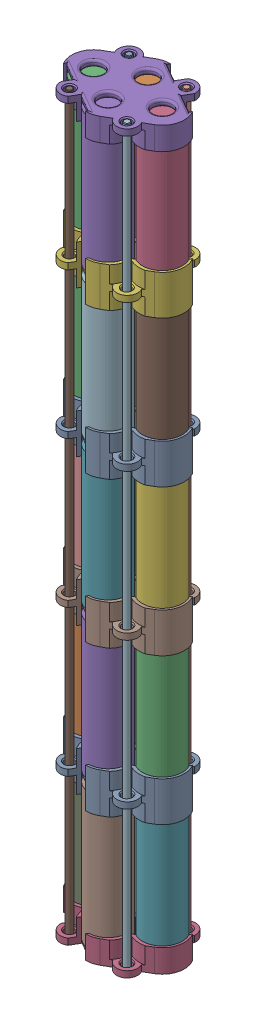
SolidWorks assembly batterySpacersAssembly_V2, configuration Default. Lengths in mm.
Overall size (58.15 352.38 42.71).
30 component instances, 6 part files, 36 mates.
Components (placement in the parent):
- batterySpacerMid-1: batterySpacerMid [Default] at (-19.5706 2.8185 8.4123) size (53.91 19 40)
- batteryCell-1: batteryCell [Default] at (-36.0251 3.8185 8.4123) x (-0.639427 0 0.768852) z (-0.768852 0 -0.639427) size (18 65 18)
- batteryCell-33: batteryCell [Default] at (-3.1161 3.8185 8.4123) x (0.922669 0 0.385592) z (-0.385592 0 0.922669) size (18 65 18)
- batteryCell-38: batteryCell [Default] at (-19.5706 3.8185 -1.0877) x (-0.259377 0 0.965776) z (-0.965776 0 -0.259377) size (18 65 18)
- batteryCell-43: batteryCell [Default] at (-19.5706 3.8185 17.9123) x (-0.999982 0 -0.006076) z (0.006076 0 -0.999982) size (18 65 18)
- batteryCell-34: batteryCell [Default] at (-3.1161 73.8185 8.4123) x (0.922669 0 0.385592) z (-0.385592 0 0.922669) size (18 65 18)
- batteryCell-44: batteryCell [Default] at (-19.5706 73.8185 17.9123) x (-0.999982 0 -0.006076) z (0.006076 0 -0.999982) size (18 65 18)
- batterySpacerMid-2: batterySpacerMid [Default] at (-19.5706 72.8185 8.4123) size (53.91 19 40)
- batteryCell-39: batteryCell [Default] at (-19.5706 73.8185 -1.0877) x (-0.259377 0 0.965776) z (-0.965776 0 -0.259377) size (18 65 18)
- batteryCell-8: batteryCell [Default] at (-36.0251 73.8185 8.4123) x (-0.639427 0 0.768852) z (-0.768852 0 -0.639427) size (18 65 18)
- batteryCell-35: batteryCell [Default] at (-3.1161 143.8185 8.4123) x (0.922669 0 0.385592) z (-0.385592 0 0.922669) size (18 65 18)
- batteryCell-45: batteryCell [Default] at (-19.5706 143.8185 17.9123) x (-0.999982 0 -0.006076) z (0.006076 0 -0.999982) size (18 65 18)
- batterySpacerMid-3: batterySpacerMid [Default] at (-19.5706 142.8185 8.4123) size (53.91 19 40)
- batteryCell-40: batteryCell [Default] at (-19.5706 143.8185 -1.0877) x (-0.259377 0 0.965776) z (-0.965776 0 -0.259377) size (18 65 18)
- batteryCell-12: batteryCell [Default] at (-36.0251 143.8185 8.4123) x (-0.639427 0 0.768852) z (-0.768852 0 -0.639427) size (18 65 18)
- batterySpacerBottom-1: batterySpacerBottom [Default] at (-19.5706 -67.1815 8.4123) size (53.91 11.13 40)
- batterySpacerTop-1: batterySpacerTop [Default] at (-19.5706 281.8185 8.4123) size (53.91 11.13 40)
- batteryCell-48: batteryCell [Default] at (-19.5706 -66.1815 -1.0877) x (0.182331 0 0.983237) z (-0.983237 0 0.182331) size (18 65 18)
- batteryCell-49: batteryCell [Default] at (-3.1161 -66.1815 8.4123) x (0.585913 0 0.810374) z (-0.810374 0 0.585913) size (18 65 18)
- batteryCell-50: batteryCell [Default] at (-19.5706 -66.1815 17.9123) x (0.644166 0 0.764886) z (-0.764886 0 0.644166) size (18 65 18)
- batteryCell-51: batteryCell [Default] at (-36.0251 -66.1815 8.4123) x (-0.258821 0 0.965925) z (-0.965925 0 -0.258821) size (18 65 18)
- threadedShaft-1: threadedShaft [Default] at (-5.8434 -70.4315 -5.864) size (3 352.25 3)
- threadedShaft-2: threadedShaft [Default] at (-33.2979 -70.4315 22.6886) size (3 352.25 3)
- threadedShaft-3: threadedShaft [Default] at (-5.8434 -70.4315 22.6886) size (3 352.25 3)
- threadedShaft-4: threadedShaft [Default] at (-33.2979 -70.4315 -5.864) size (3 352.25 3)
- batteryCell-41: batteryCell [Default] at (-19.5706 213.8185 -1.0877) x (-0.259377 0 0.965776) z (-0.965776 0 -0.259377) size (18 65 18)
- batteryCell-31: batteryCell [Default] at (-36.0251 213.8185 8.4123) x (-0.639427 0 0.768852) z (-0.768852 0 -0.639427) size (18 65 18)
- batteryCell-36: batteryCell [Default] at (-3.1161 213.8185 8.4123) x (0.922669 0 0.385592) z (-0.385592 0 0.922669) size (18 65 18)
- batteryCell-46: batteryCell [Default] at (-19.5706 213.8185 17.9123) x (-0.999982 0 -0.006076) z (0.006076 0 -0.999982) size (18 65 18)
- batterySpacerMid_BMS_holder-1: batterySpacerMid_BMS_holder [Default] at (-19.5706 212.8185 8.4123) size (53.91 19 40)
Mates (geometry in assembly coordinates):
- Concentric1: concentric anti-aligned: cylinder of batterySpacerMid-1 through (-36.0251 -64.4158 8.4123) axis (0 1 0) radius 9.5; cylinder of batteryCell-1 through (-36.0251 68.8185 8.4123) axis (0 -1 0) radius 9
- Concentric2: concentric anti-aligned: cylinder of batterySpacerMid-1 through (-19.5706 -64.4158 17.9123) axis (0 1 0) radius 9.5; cylinder of batteryCell (1)-22 through (-19.5706 68.8185 17.9123) axis (0 -1 0) radius 9
- Concentric3: concentric anti-aligned: cylinder of batterySpacerMid-1 through (-19.5706 -64.4158 -1.0877) axis (0 1 0) radius 9.5; cylinder of batteryCell-3 through (-19.5706 68.8185 -1.0877) axis (0 -1 0) radius 9
- Concentric4: concentric anti-aligned: cylinder of batterySpacerMid-1 through (-3.1161 -64.4158 8.4123) axis (0 1 0) radius 9.5; cylinder of batteryCell-2 through (-3.1161 68.8185 8.4123) axis (0 -1 0) radius 9
- Distance1: distance = 1 mm anti-aligned: plane of batteryCell-1 through (-36.0251 3.8185 8.4123) normal (0 -1 0); plane of batterySpacerMid-1 through (-19.5706 2.8185 8.4123) normal (0 1 0)
- Distance2: distance = 1 mm anti-aligned: plane of batteryCell (1)-22 through (-19.5706 3.8185 17.9123) normal (0 -1 0); plane of batterySpacerMid-1 through (-19.5706 2.8185 8.4123) normal (0 1 0)
- Distance3: distance = 1 mm anti-aligned: plane of batteryCell-2 through (-3.1161 3.8185 8.4123) normal (0 -1 0); plane of batterySpacerMid-1 through (-19.5706 2.8185 8.4123) normal (0 1 0)
- Distance4: distance = 1 mm anti-aligned: plane of batteryCell-3 through (-19.5706 3.8185 -1.0877) normal (0 -1 0); plane of batterySpacerMid-1 through (-19.5706 2.8185 8.4123) normal (0 1 0)
- Coincident6: coincident anti-aligned: plane of batterySpacerTop-1 through (-19.5706 278.8185 8.4123) normal (0 -1 0); plane of batteryCell-16 through (-3.1161 278.8185 8.4123) normal (0 1 0)
- Concentric6: concentric anti-aligned: cylinder of batterySpacerTop-1 through (-36.0251 214.5842 8.4123) axis (0 1 0) radius 9.5; cylinder of batteryCell-13 through (-36.0251 278.8185 8.4123) axis (0 -1 0) radius 9
- Concentric7: concentric anti-aligned: cylinder of batterySpacerTop-1 through (-19.5706 214.5842 17.9123) axis (0 1 0) radius 9.5; cylinder of batteryCell-15 through (-19.5706 278.8185 17.9123) axis (0 -1 0) radius 9
- Concentric14: concentric anti-aligned: cylinder of batterySpacerMid-1 through (-19.5706 -64.4158 -1.0877) axis (0 1 0) radius 9.5; cylinder of batteryCell-17 through (-19.5706 -1.1815 -1.0877) axis (0 -1 0) radius 9
- Concentric15: concentric anti-aligned: cylinder of batterySpacerMid-1 through (-36.0251 -64.4158 8.4123) axis (0 1 0) radius 9.5; cylinder of batteryCell-23 through (-36.0251 -1.1815 8.4123) axis (0 -1 0) radius 9
- Concentric16: concentric anti-aligned: cylinder of batterySpacerMid-1 through (-3.1161 -64.4158 8.4123) axis (0 1 0) radius 9.5; cylinder of batteryCell-21 through (-3.1161 -1.1815 8.4123) axis (0 -1 0) radius 9
- Concentric17: concentric anti-aligned: cylinder of batterySpacerMid-1 through (-19.5706 -23.0659 17.9123) axis (0 1 0) radius 9.5; cylinder of batteryCell-22 through (-19.5706 -1.1815 17.9123) axis (0 -1 0) radius 9
- Distance9: distance = 1 mm anti-aligned: plane of batteryCell-21 through (-3.1161 -1.1815 8.4123) normal (0 1 0); plane of batterySpacerMid-1 through (-19.5706 -0.1815 8.4123) normal (0 -1 0)
- Distance10: distance = 1 mm anti-aligned: plane of batteryCell-22 through (-19.5706 -1.1815 17.9123) normal (0 1 0); plane of batterySpacerMid-1 through (-19.5706 -0.1815 8.4123) normal (0 -1 0)
- Distance11: distance = 1 mm anti-aligned: plane of batteryCell-23 through (-36.0251 -1.1815 8.4123) normal (0 1 0); plane of batterySpacerMid-1 through (-19.5706 -0.1815 8.4123) normal (0 -1 0)
- Distance12: distance = 1 mm anti-aligned: plane of batteryCell-17 through (-19.5706 -1.1815 -1.0877) normal (0 1 0); plane of batterySpacerMid-1 through (-19.5706 -0.1815 8.4123) normal (0 -1 0)
- Concentric18: concentric anti-aligned: cylinder of batterySpacerBottom-1 through (-3.1161 -134.4158 8.4123) axis (0 1 0) radius 9.5; cylinder of batteryCell-21 through (-3.1161 -1.1815 8.4123) axis (0 -1 0) radius 9
- Concentric19: concentric anti-aligned: cylinder of batterySpacerBottom-1 through (-19.5706 -134.4158 -1.0877) axis (0 1 0) radius 9.5; cylinder of batteryCell-17 through (-19.5706 -1.1815 -1.0877) axis (0 -1 0) radius 9
- Distance13: distance = 1 mm anti-aligned: plane of batterySpacerBottom-1 through (-19.5706 -67.1815 8.4123) normal (0 1 0); plane of batteryCell-17 through (-19.5706 -66.1815 -1.0877) normal (0 -1 0)
- Concentric20: concentric anti-aligned: cylinder of batterySpacerTop-1 through (-5.8434 270.8175 -5.864) axis (0 1 0) radius 2.2; cylinder of threadedShaft-1 through (-5.8434 281.8185 -5.864) axis (0 -1 0) radius 1.5
- Concentric21: concentric anti-aligned: cylinder of batterySpacerTop-1 through (-33.2979 270.8175 -5.864) axis (0 1 0) radius 2.2; cylinder of threadedShaft-4 through (-33.2979 281.8185 -5.864) axis (0 -1 0) radius 1.5
- Concentric22: concentric anti-aligned: cylinder of batterySpacerTop-1 through (-33.2979 270.8175 22.6886) axis (0 1 0) radius 2.2; cylinder of threadedShaft-2 through (-33.2979 281.8185 22.6886) axis (0 -1 0) radius 1.5
- Concentric23: concentric anti-aligned: cylinder of batterySpacerTop-1 through (-5.8434 270.8175 22.6886) axis (0 1 0) radius 2.2; cylinder of threadedShaft-3 through (-5.8434 281.8185 22.6886) axis (0 -1 0) radius 1.5
- Coincident7: coincident aligned: plane of batterySpacerTop-1 through (-19.5706 281.8185 8.4123) normal (0 1 0); plane of threadedShaft-3 through (-5.8434 281.8185 22.6886) normal (0 1 0)
- Coincident8: coincident aligned: plane of batterySpacerTop-1 through (-19.5706 281.8185 8.4123) normal (0 1 0); plane of threadedShaft-1 through (-5.8434 281.8185 -5.864) normal (0 1 0)
- Coincident9: coincident aligned: plane of batterySpacerTop-1 through (-19.5706 281.8185 8.4123) normal (0 1 0); plane of threadedShaft-4 through (-33.2979 281.8185 -5.864) normal (0 1 0)
- Coincident10: coincident aligned: plane of batterySpacerTop-1 through (-19.5706 281.8185 8.4123) normal (0 1 0); plane of threadedShaft-2 through (-33.2979 281.8185 22.6886) normal (0 1 0)
- Concentric24: concentric anti-aligned: cylinder of threadedShaft-2 through (-33.2979 281.8185 22.6886) axis (0 -1 0) radius 1.5; circle of batterySpacerMid, BMS holder-1
- Concentric25: concentric anti-aligned: cylinder of threadedShaft-3 through (-5.8434 281.8185 22.6886) axis (0 -1 0) radius 1.5; cylinder of batterySpacerMid_BMS_holder-1 through (-5.8434 201.8175 22.6886) axis (0 1 0) radius 2.0625
- Concentric27: concentric anti-aligned: circle of batterySpacerMid-3; cylinder of threadedShaft-2 through (-33.2979 281.8185 22.6886) axis (0 -1 0) radius 1.5
- Concentric28: concentric anti-aligned: circle of batterySpacerMid-3; cylinder of threadedShaft-3 through (-5.8434 281.8185 22.6886) axis (0 -1 0) radius 1.5
- Width1: width aligned: plane of batterySpacerMid, BMS holder-1 through (-19.5706 212.8185 8.4123) normal (0 1 0); plane of batteryCell (1)-24 through (-19.5706 209.8185 8.4123) normal (0 -1 0); plane of batterySpacerMid, BMS holder-1 through (-19.5706 208.8185 17.9123) normal (0 1 0); plane of batteryCell (1)-33 through (-19.5706 213.8185 17.9123) normal (0 -1 0)
- Coincident12: coincident anti-aligned: plane of batterySpacerTop-1 through (-19.5706 278.8185 8.4123) normal (0 -1 0); plane of batteryCell (1)-33 through (-19.5706 278.8185 17.9123) normal (0 1 0)
